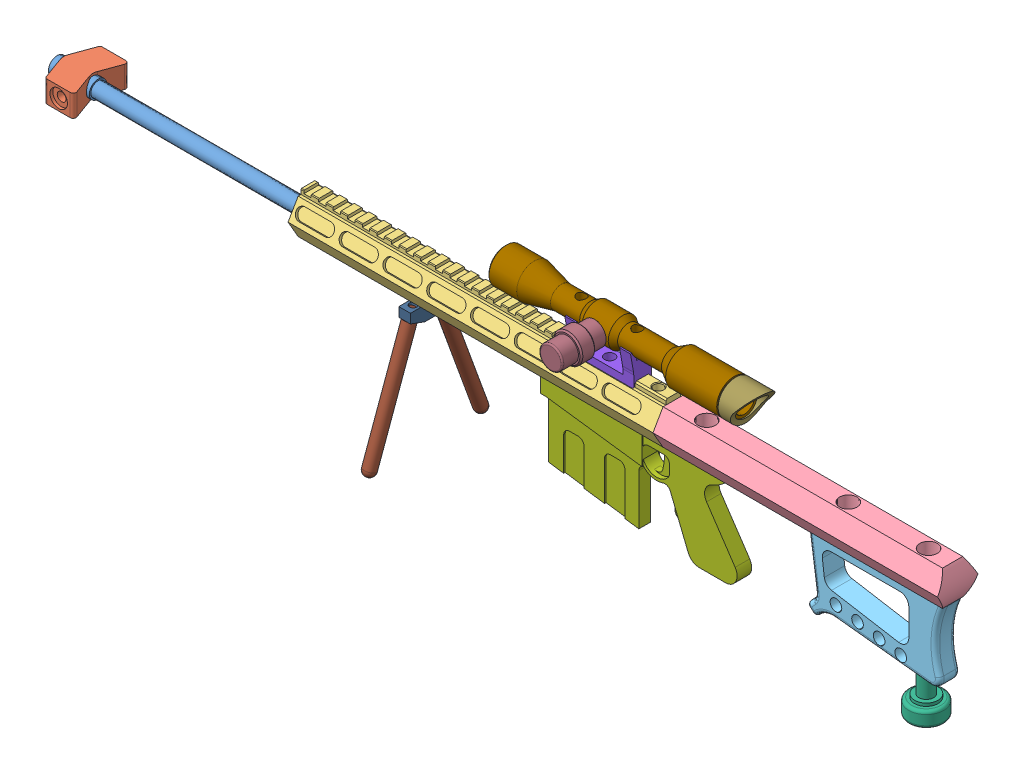
SolidWorks assembly M28A1, configuration 默认. Lengths in mm.
Overall size (617 149.8 87.34).
14 component instances, 13 part files, 33 mates.
Components (placement in the parent):
- BATTLE枪管-1: BATTLE枪管 [默认] at (21.5518 -3.9734 0) size (187 12 12)
- 制退器-1: 制退器 [默认] at (-153.1256 -11.4734 0) x (0 0 -1) z (1 0 0) size (38 15 25.55)
- 上机匣-1: 上机匣 [默认] at (256.5518 -3.9734 0) x (0 1 0) z (1 0 0) size (27.5 27.71 250)
- 下机匣-1: 下机匣 [默认] at (451.5518 -3.9734 0) x (0 1 0) z (0 0 -1) size (24 215 27.71)
- 枪托-1: 枪托 [默认] at (355.1454 -15.9734 -7.5988) x (1 0 -0.000838) z (0.000838 0 1) size (93.82 50.95 14.61)
- 支脚-1: 支脚 [默认] at (429.3978 -53.4734 -0.5859) x (0 1 0) z (-0.999999 0 0.00153) size (40 24 24)
- 握把-1: 握把 [默认] at (171.5518 -12.9317 0) size (133.83 64 12)
- 支架-1: 支架 [默认] at (213.0518 12.5266 0) x (1 0 0) z (0 -1 0) size (45 16.5 22)
- 瞄准镜-1: 瞄准镜 [默认] at (305.3614 31.5266 0) x (-1 0 0) z (0 -0.000046 1) size (164 24 24)
- 连接块-1: 连接块 [默认] at (82.5518 -15.9734 14) x (0 0 -1) z (-1 0 0) size (28 10 8)
- 脚架-1: 脚架 [默认] at (86.5518 -16.9529 8.3169) x (0 -0.939693 0.34202) z (-0.999418 0.011663 0.032045) size (91 8 8)
- 脚架-2: 脚架 [默认] at (86.5518 -16.9529 -8.3169) x (0 -0.939693 -0.34202) z (0.248575 -0.331285 0.910198) size (91 8 8)
- 目镜-1: 目镜 [默认] at (298.3614 31.5266 0) x (0 -0.155824 -0.987785) z (1 0 0) size (24 24 21)
- 调整钮-1: 调整钮 [默认] at (212.6493 31.5105 40) x (0 0.000403 -1) z (0.722459 -0.691413 -0.000278) size (40 20 20)
Mates (geometry in assembly coordinates):
- 同心2: concentric: cylinder of BATTLE枪管-1 through (-145.4482 -3.9734 28) axis (0 0 -1) radius 3; cylinder of 制退器-1 through (-145.4482 -3.9734 1) axis (0 0 -1) radius 3
- 同心6: concentric: cylinder of BATTLE枪管-1 through (8.5518 -3.9734 0) axis (1 0 0) radius 4; cylinder of 上机匣-1 through (6.5518 -3.9734 0) axis (-1 0 0) radius 3.4
- 重合1: coincident: plane of BATTLE枪管-1 through (6.5518 -3.9734 0) normal (1 0 0); plane of 上机匣-1 through (6.5518 -3.9734 0) normal (-1 0 0)
- 垂直4: perpendicular: plane of 制退器-1 through (-137.5733 3.5266 -17) normal (0 1 0); plane of 上机匣-1 through (6.5518 -3.9734 0) normal (-1 0 0)
- 平行9: parallel: plane of 制退器-1 through (-137.5733 3.5266 -17) normal (0 1 0); plane of 上机匣-1 through (256.5518 7.5266 0) normal (0 1 0)
- 同心7: concentric: cylinder of BATTLE枪管-1 through (-165.4482 -3.9734 0) axis (-1 0 0) radius 4; cylinder of 制退器-1 through (-168.1256 -3.9734 0) axis (1 0 0) radius 6
- 重合23: coincident: plane of 上机匣-1 through (256.5518 -3.9734 0) normal (1 0 0); plane of 下机匣-1 through (256.5518 -3.9734 0) normal (-1 0 0)
- 同心8: concentric: circle of 上机匣-1; circle of 下机匣-1
- 重合26: coincident: plane of 上机匣-1 through (6.5518 8.0266 -6.9282) normal (0 1 0); plane of 下机匣-1 through (256.5518 8.0266 -6.9282) normal (0 1 0)
- 平行18: parallel: plane of 下机匣-1 through (256.5518 -15.9734 6.9282) normal (0 -1 0); plane of 枪托-1 through (355.1571 -15.9734 6.4012) normal (0 1 0)
- 同心11: concentric: circle of 下机匣-1; circle of 枪托-1
- 同心12: concentric: circle of 下机匣-1; circle of 枪托-1
- 重合27: coincident: plane of 下机匣-1 through (256.5518 -15.9734 6.9282) normal (0 -1 0); plane of 枪托-1 through (355.1571 -15.9734 6.4012) normal (0 1 0)
- 同心14: concentric: cylinder of 枪托-1 through (429.3978 -63.4734 -0.5859) axis (0 -1 0) radius 3.4; cylinder of 支脚-1 through (429.3978 -121.0375 -0.5859) axis (0 -1 0) radius 4
- 重合28: coincident: plane of 枪托-1 through (355.1454 -63.4734 -7.5988) normal (0 -1 0); plane of 支脚-1 through (429.3928 -63.4734 -3.8359) normal (0 1 0)
- 同心15: concentric: circle of 下机匣-1; cylinder of 握把-1 through (279.5518 -12.9317 0) axis (0 1 0) radius 2.5
- 同心17: concentric: cylinder of 上机匣-1 through (191.5518 11.5266 0) axis (0 1 0) radius 3.25; cylinder of 握把-1 through (191.5518 -12.9317 0) axis (0 1 0) radius 2.5
- 同心20: concentric: cylinder of 上机匣-1 through (213.0518 7.5266 0) axis (0 1 0) radius 2.5; cylinder of 支架-1 through (213.0518 7.5266 0) axis (0 1 0) radius 3.5
- 重合30: coincident: plane of 上机匣-1 through (256.5518 7.5266 0) normal (0 1 0); plane of 支架-1 through (213.0518 7.5266 0) normal (0 -1 0)
- 重合33: coincident: plane of 上机匣-1 through (235.5518 7.5266 6.9282) normal (-1 0 0); plane of 支架-1 through (235.5518 7.5266 -6) normal (1 0 0)
- 同心21: concentric: cylinder of 支架-1 through (232.0518 23.5266 0) axis (0 1 0) radius 2.5; cylinder of 瞄准镜-1 through (232.0518 24.0266 0) axis (0 -1 0) radius 3.25
- 同心24: concentric: cylinder of 支架-1 through (228.0518 31.5266 0) axis (1 0 0) radius 7; cylinder of 瞄准镜-1 through (305.3614 31.5266 0) axis (1 0 0) radius 7.5
- 同心25: concentric: cylinder of 上机匣-1 through (86.5518 -15.9734 0) axis (0 -1 0) radius 2.5; cylinder of 连接块-1 through (86.5518 -25.9734 0) axis (0 -1 0) radius 2.5
- 重合34: coincident: plane of 上机匣-1 through (6.5518 -15.9734 6.9282) normal (0 -1 0); plane of 连接块-1 through (90.5518 -15.9734 14) normal (0 1 0)
- 平行23: parallel: plane of 上机匣-1 through (6.5518 8.0266 5) normal (0 0 1); plane of 连接块-1 through (90.5518 -22.3337 14) normal (0 0 1)
- 同心26: concentric: cylinder of 连接块-1 through (86.5518 -23.5308 10.7111) axis (0 -0.939693 0.34202) radius 2.5; cylinder of 脚架-1 through (86.5518 -16.9529 8.3169) axis (0 0.939693 -0.34202) radius 3
- 重合40: coincident: plane of 连接块-1 through (90.5518 -25.9734 4) normal (0 -0.939693 0.34202); plane of 脚架-1 through (86.637 -22.6762 13.0589) normal (0 0.939693 -0.34202)
- 同心27: concentric: cylinder of 连接块-1 through (86.5518 -23.5308 -10.7111) axis (0 -0.939693 -0.34202) radius 2.5; cylinder of 脚架-2 through (86.5518 -16.9529 -8.3169) axis (0 0.939693 0.34202) radius 3
- 重合41: coincident: plane of 连接块-1 through (90.5518 -25.9734 -4) normal (0 -0.939693 -0.34202); plane of 脚架-2 through (88.9733 -23.3182 -11.295) normal (0 0.939693 0.34202)
- 同心28: concentric: cylinder of 瞄准镜-1 through (305.3614 31.5266 0) axis (1 0 0) radius 10; cylinder of 目镜-1 through (298.3614 31.5266 0) axis (-1 0 0) radius 8.75
- 重合42: coincident: plane of 瞄准镜-1 through (298.3614 31.5266 0) normal (1 0 0); circle of 目镜-1
- 同心29: concentric: cylinder of 瞄准镜-1 through (212.6493 31.5226 10) axis (0 -0.000403 1) radius 5.1; cylinder of 调整钮-1 through (212.6493 31.5105 40) axis (0 -0.000403 1) radius 6
- 相切2: tangent: cylinder of 瞄准镜-1 through (305.3614 31.5266 0) axis (1 0 0) radius 10; plane of 调整钮-1 through (218.1806 37.3022 10.0023) normal (0 0.000403 -1)
